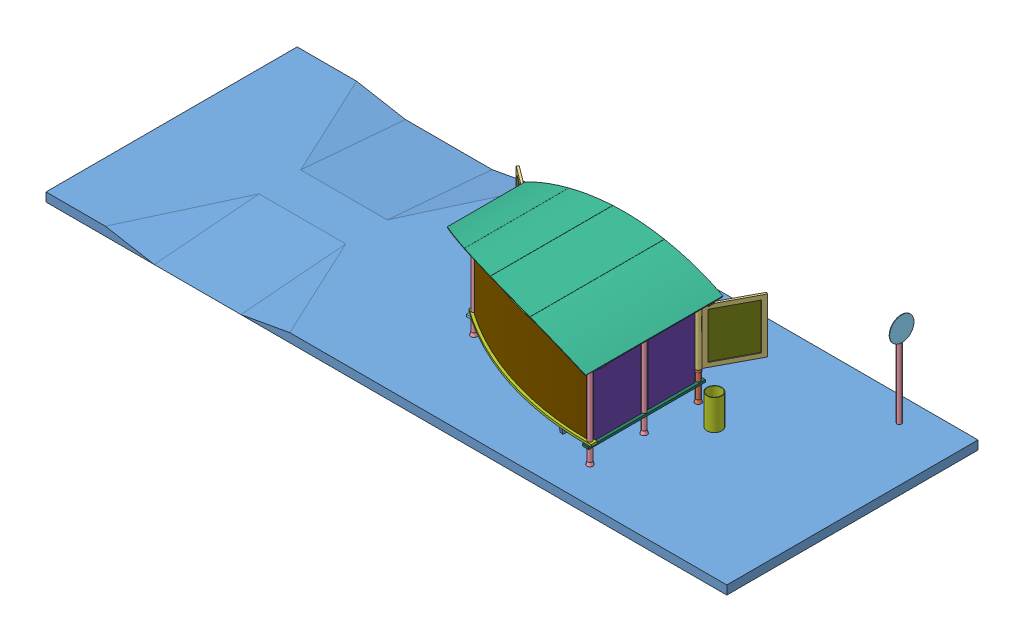
SolidWorks assembly Assem1, configuration Default. Lengths in mm.
Overall size (15720 3533.42 6503.13).
36 component instances, 25 part files, 159 mates.
Components (placement in the parent):
- Footh path-1: Footh path [Default] at (-2438.0582 7057.9484 15911.0305) size (15720 203.2 5800)
- Pole ring-1: Pole ring [Default] at (9292.5752 7335.7894 12581.0305) x (0.589726 0 -0.807604) z (0.807604 0 0.589726) size (140 2610 140)
- Frame-1: Frame [Default] at (9292.5752 7935.7894 12581.0305) x (0.469771 0 -0.882788) z (0.882788 0 0.469771) size (1235 1260 120)
- Pole-1: Pole [Default] at (9292.5752 7335.7894 13831.0305) x (0.069231 0 -0.997601) z (0.997601 0 0.069231) size (140 2610 140)
- Pole-2: Pole [Default] at (9292.5752 7335.7894 15081.0305) x (0.865127 0 -0.501553) z (0.501553 0 0.865127) size (140 2610 140)
- Pole ring-2: Pole ring [Default] at (5362.5752 7335.7894 12581.0305) x (0.936618 0 -0.350353) z (0.350353 0 0.936618) size (140 2610 140)
- Frame-2: Frame [Default] at (5362.5752 7935.7894 12581.0305) x (-0.801865 0 -0.597505) z (0.597505 0 -0.801865) size (1235 1260 120)
- Support small-3: Support small [Default] at (5292.5752 9335.7894 16511.0305) x (0 0 -1) z (0 -1 0) size (1450 140 50)
- Pole-3: Pole [Default] at (5362.5752 7335.7894 13831.0305) x (-0.993477 0 0.114032) z (-0.114032 0 -0.993477) size (140 2610 140)
- Support-1: Support [Default] at (5362.5752 9395.7894 12651.0305) x (1 0 0) z (0 1 0) size (4130 140 50)
- Curved long Support-1: Curved long Support [Default] at (9292.5752 9395.7894 15081.0305) x (0.865101 0 -0.501598) z (0 1 0) size (2988.63 3350.69 50)
- Curved long Support-2: Curved long Support [Default] at (9292.5752 7692.0618 15081.0305) x (0.865101 0 -0.501598) z (0 1 0) size (2988.63 3350.69 50)
- Curved long Shed 2-1: Curved long Shed 2 [Default] at (5878.003 7237.9254 16191.0495) x (1 0 0) z (0 1 0) size (4530 1976.71 909.5)
- Shed-1: Shed [Default] at (5362.5752 9395.7894 12651.0305) x (1 0 0) z (0 1 0) size (4530 140 567.45)
- Strips 1-1: Strips 1 [Default] at (-11146.362 19849.8743 2384.7532) x (0.892652 -0.450746 0) z (0 0 1) size (200 25 2933.57)
- Strips 2-3: Strips 2 [Default] at (-13429.2364 13763.5915 2384.7532) x (0.983949 -0.17845 0) z (0 0 1) size (200 25 2891)
- Strips 3-1: Strips 3 [Default] at (-13731.0289 8733.7477 2384.7532) x (0.998403 0.056486 0) z (0 0 1) size (200 25 2656.85)
- Strips 4-1: Strips 4 [Default] at (-12840.3126 4462.485 2384.7532) x (0.962952 0.269673 0) z (0 0 1) size (200 25 2167.26)
- Strips 5-1: Strips 5 [Default] at (-11819.7292 1327.6603 2384.7532) x (0.902606 0.430469 0) z (0 0 1) size (200 25 1693.64)
- Support Double-2: Support Double [Default] at (32225.5198 7642.0618 25262.0609) x (0 0 1) z (-1 0 0) size (2700 50 140)
- Support small-4: Support small [Default] at (5292.5752 7702.0618 9901.0305) x (0 0 1) z (0 1 0) size (1450 140 50)
- Support Double-3: Support Double [Default] at (32225.5198 9345.7894 25262.0609) x (0 0 1) z (-1 0 0) size (2700 50 140)
- Glass frame-2: Glass frame [Default] at (14070.0925 -425.359 3592.5383) x (0.469771 0 -0.882788) z (0.882788 0 0.469771) size (909.76 1060 10)
- Glass frame-3: Glass frame [Default] at (-2802.8168 -425.359 6502.8697) x (-0.801865 0 -0.597505) z (0.597505 0 -0.801865) size (909.76 1060 10)
- Glass-3: Glass [Default] at (5367.5752 -370.078 25234.791) x (0 0 1) z (-1 0 0) size (1092.11 1709.01 10)
- Glass-4: Glass [Default] at (9287.5752 -370.078 2415.1587) x (0 0 -1) z (1 0 0) size (1092.11 1709.01 10)
- Glass-5: Glass [Default] at (9287.5752 -370.078 1165.1587) x (0 0 -1) z (1 0 0) size (1092.11 1709.01 10)
- Glass back-1: Glass back [Default] at (9292.5752 9395.7894 15081.0305) x (-0.865101 0 0.501598) z (0 -1 0) size (2682.66 2948.43 1653.73)
- bench-3: bench [Default] at (9292.5752 7261.1484 8278.0705) x (0.573924 0 -0.818909) z (0.818909 0 0.573924) size (1386.88 534.65 3037.44)
- Ad-1: Ad [Default] at (5367.5752 -370.078 25234.791) x (0 0 -1) z (1 0 0) size (967.13 1402.54 20)
- Map-2: Map [Default] at (461.3046 8443.7494 -490.4565) x (0.998536 0 0.054083) z (0 1 0) size (746.38 115.58 600)
- RTPI-2: RTPI [Default] at (-2205.7822 9395.7894 9253.0974) x (1 0 0) z (0 -1 0) size (2045.3 249.56 600)
- Pole-4: Pole [Default] at (12031.85 7058.8113 10678.6301) size (140 2610 140)
- Sign board-2: Sign board [Default] at (11984.6264 -4.3155 21348.2902) x (-0.009112 0 0.999958) z (-0.999958 0 -0.009112) size (557.79 557.79 10)
- Part1-1: Part1 [Default] at (-13731.0289 8733.7477 12327.336) x (-0.998403 -0.056486 0) z (0 0 -1) size (4558.63 692.88 3411.91)
- Bin-1: Bin [Default] at (-2438.0582 7261.1484 15911.0305) x (1 0 0) z (0 1 0) size (342.37 342.37 700)
Mates (geometry in assembly coordinates):
- Coincident1: coincident: plane of Pole ring-1 through (9292.5752 9195.7894 12581.0305) normal (0 -1 0); plane of Frame-1 through (9269.0866 9195.7894 12625.1699) normal (0 1 0)
- Concentric2: concentric: cylinder of Pole ring-1 through (22932.9446 7761.1484 10181.0305) axis (0 -1 0) radius 50; cylinder of ? through (22932.9446 9671.1484 10181.0305) axis (0 1 0) radius 50
- Coincident3: coincident: plane of Pole ring-1 through (22932.9446 9671.1484 10181.0305) normal (0 1 0); plane of ? through (22862.9446 9671.1484 7501.0305) normal (0 -1 0)
- Concentric3: concentric: cylinder of Pole-1 through (22932.9446 7761.1484 11431.0305) axis (0 -1 0) radius 50; cylinder of ? through (22932.9446 9671.1484 11431.0305) axis (0 1 0) radius 50
- Concentric4: concentric: cylinder of Pole-2 through (22932.9446 7761.1484 12681.0305) axis (0 -1 0) radius 50; cylinder of ? through (22932.9446 9721.1484 12681.0305) axis (0 1 0) radius 50
- Concentric5: concentric: cylinder of Pole-1 through (22932.9446 7761.1484 11431.0305) axis (0 -1 0) radius 50; cylinder of ? through (22932.9446 9721.1484 11431.0305) axis (0 1 0) radius 50
- Coincident5: coincident: plane of ? through (22862.9446 9721.1484 7501.0305) normal (0 1 0); plane of ? through (23002.9446 9721.1484 15361.0305) normal (0 -1 0)
- Concentric6: concentric: cylinder of Pole ring-2 through (5362.5752 7335.7894 12581.0305) axis (0 -1 0) radius 50; cylinder of Frame-2 through (5362.5752 7935.7894 12581.0305) axis (0 -1 0) radius 50
- Coincident9: coincident: plane of Pole ring-2 through (5362.5752 7935.7894 12581.0305) normal (0 1 0); plane of Frame-2 through (5410.6871 7935.7894 12616.8808) normal (0 -1 0)
- Coincident12: coincident: circle of Support small-3; cylinder of Pole-3 through (5362.5752 7335.7894 13831.0305) axis (0 -1 0) radius 50
- Concentric7: concentric: cylinder of Pole ring-2 through (5362.5752 7335.7894 12581.0305) axis (0 -1 0) radius 50; cylinder of Support small-3 through (5362.5752 9395.7894 12581.0305) axis (0 -1 0) radius 50
- Concentric12: concentric: cylinder of Pole ring-1 through (9265.3997 7761.1484 10181.0305) axis (0 -1 0) radius 50; cylinder of ? through (9265.3997 7307.2509 10181.0305) axis (0 1 0) radius 50
- Concentric13: concentric: cylinder of Pole ring-2 through (5335.3997 7761.1484 10181.0305) axis (0 -1 0) radius 50; cylinder of ? through (5335.3997 7307.2509 10181.0305) axis (0 1 0) radius 50
- Perpendicular5: perpendicular: plane of Support small-3 through (5405.3997 9721.1484 11531.0305) normal (1 0 0); plane of ? through (9265.3997 7357.2509 10251.0305) normal (0 0 1)
- Parallel3: parallel: plane of ? through (22862.9446 9671.1484 11531.0305) normal (-1 0 0); plane of ? through (22862.9446 9721.1484 12781.0305) normal (-1 0 0)
- InPlace2: in place: plane of ? through (9215.5775 9871.1484 12676.8176) normal (0 1 0); plane of ? through (0 9871.1484 0) normal (0 1 0); moOrthogonalPlaneRef_w of ? through (9215.5775 9871.1484 12676.8176) normal (0 1 0); plane of ? through (0 9871.1484 0) normal (0 0 -1); plane of ? through (9215.5775 9871.1484 12676.8176) normal (0 1 0); plane of ? through (0 9871.1484 0) normal (1 0 0); plane of ? through (11383.7389 9871.1484 12693.4409) normal (0 1 0); unknown of ?
- Coincident31: coincident: plane of Pole-2; plane of ?
- Coincident32: coincident: moOrthogonalPlaneRef_w of Pole-2; plane of ? through (11432.1742 9871.1484 12681.0305) normal (-0.248209 0 -0.968706)
- Coincident33: coincident: moOrthogonalPlaneRef_w of Pole-2; plane of ? through (11432.1742 9871.1484 12681.0305) normal (0.968706 0 -0.248209)
- Concentric14: concentric: cylinder of Pole ring-1 through (9292.5752 7335.7894 12581.0305) axis (0 -1 0) radius 50; cylinder of Support-1 through (9292.5752 9395.7894 12581.0305) axis (0 1 0) radius 50
- Concentric15: concentric: cylinder of Pole ring-2 through (5362.5752 7335.7894 12581.0305) axis (0 -1 0) radius 50; cylinder of Support-1 through (5362.5752 9395.7894 12581.0305) axis (0 1 0) radius 50
- Perpendicular6: perpendicular: plane of Support small-3 through (5432.5752 9395.7894 13931.0305) normal (1 0 0); plane of Support-1 through (9292.5752 9445.7894 12651.0305) normal (0 0 1)
- Concentric16: concentric: cylinder of Pole-2 through (9292.5752 7335.7894 15081.0305) axis (0 -1 0) radius 50; cylinder of Curved long Support-1 through (9292.5752 9445.7894 15081.0305) axis (0 -1 0) radius 50
- Concentric17: concentric: cylinder of Pole-3 through (5362.5752 7335.7894 13831.0305) axis (0 -1 0) radius 50; cylinder of Curved long Support-1 through (5362.5752 9445.7894 13831.0305) axis (0 -1 0) radius 50
- Concentric38: concentric: cylinder of Support Double-3 through (9292.5752 9395.7894 15081.0305) axis (0 -1 0) radius 50; cylinder of Pole-2 through (9292.5752 7335.7894 15081.0305) axis (0 -1 0) radius 50
- Concentric19: concentric: cylinder of Pole-3 through (5362.5752 7335.7894 13831.0305) axis (0 -1 0) radius 50; cylinder of Curved long Support-2 through (5362.5752 7742.0618 13831.0305) axis (0 -1 0) radius 50
- Concentric21: concentric: cylinder of Pole-3 through (5362.5752 7335.7894 13831.0305) axis (0 -1 0) radius 50; cylinder of Curved long Shed 2-1 through (5362.5752 10237.9254 13831.0305) axis (0 -1 0) radius 50
- Tangent1: tangent: cylinder of Shed-1 through (9292.5752 9917.1343 12581.0305) axis (0 -1 0) radius 50; cylinder of Pole ring-1 through (9292.5752 7335.7894 12581.0305) axis (0 -1 0) radius 50
- Concentric22: concentric: cylinder of Pole ring-2 through (5362.5752 7335.7894 12581.0305) axis (0 -1 0) radius 50; cylinder of Shed-1 through (5362.5752 9917.1343 12581.0305) axis (0 -1 0) radius 50
- Concentric23: concentric: cylinder of Curved long Shed 2-1 through (7327.5752 4892.1343 13191.0495) axis (0 0 1) radius 5025; cylinder of Shed-1 through (7327.5752 4892.1343 12511.0305) axis (0 0 1) radius 5025
- Coincident45: coincident: line of Curved long Support-1 through (9392.5752 9445.7894 15150.3029) axis (0 0 -1); cylinder of Curved long Shed 2-1 through (7327.5752 4892.1343 13191.0495) axis (0 0 1) radius 5000
- Lock1: lock: unknown of Pole-2; unknown of Curved long Support-2
- InPlace3: in place: plane of assembly through (0 0 0) normal (0 0 1); plane of assembly through (0 0 0) normal (0 1 0); plane of assembly through (0 0 0) normal (1 0 0); unknown of assembly
- Coincident47: coincident: plane of ?; plane of assembly
- Coincident48: coincident: plane of ?; moOrthogonalPlaneRef_w of assembly through (0 0 0) normal (0 1 0)
- Coincident49: coincident: plane of ?; moOrthogonalPlaneRef_w of assembly through (0 0 0) normal (1 0 0)
- Tangent2: tangent: cylinder of Shed-1 through (7327.5752 4892.1343 12511.0305) axis (0 0 1) radius 5025; plane of Strips 1-1 through (-11146.362 19849.8743 2384.7532) normal (-0.450746 -0.892652 0)
- Tangent3: tangent: cylinder of Curved long Shed 2-1 through (7327.5752 4892.1343 13191.0495) axis (0 0 1) radius 5025; plane of Strips 1-1 through (-11146.362 19849.8743 2384.7532) normal (-0.450746 -0.892652 0)
- Coincident46: coincident: line of Shed-1 through (9592.5752 9377.7111 12511.0305) axis (0 0 1); line of Strips 1-1 through (9592.5752 9377.7111 15260.9099) axis (0 0 -1)
- Tangent4: tangent: cylinder of Shed-1 through (7327.5752 4892.1343 12511.0305) axis (0 0 1) radius 5025; plane of Strips 2-3 through (-13429.2364 13763.5915 2384.7532) normal (-0.17845 -0.983949 0)
- Parallel7: parallel: plane of Strips 1-1 through (9603.8438 9400.0275 12327.336) normal (0 0 -1); plane of Strips 2-3 through (8352.9117 9838.5581 12327.336) normal (0 0 -1)
- Tangent5: tangent: cylinder of Shed-1 through (7327.5752 4892.1343 12511.0305) axis (0 0 1) radius 5025; plane of Strips 3-1 through (-13731.0289 8733.7477 2384.7532) normal (0.056486 -0.998403 0)
- Tangent6: tangent: cylinder of Shed-1 through (7327.5752 4892.1343 12511.0305) axis (0 0 1) radius 5025; plane of Strips 4-1 through (-12840.3126 4462.485 2384.7532) normal (0.269673 -0.962952 0)
- Tangent7: tangent: cylinder of Shed-1 through (7327.5752 4892.1343 12511.0305) axis (0 0 1) radius 5025; plane of Strips 5-1 through (-11819.7292 1327.6603 2384.7532) normal (0.430469 -0.902606 0)
- InPlace4: in place: plane of ? through (0 0 0) normal (1 0 0); plane of ? through (0 0 0) normal (0 1 0); plane of ? through (0 0 0) normal (0 0 -1); unknown of ?
- Coincident49: coincident: plane of ?; plane of assembly
- Coincident50: coincident: plane of ? through (0 0 0) normal (0 1 0)
- Coincident51: coincident: plane of ? through (0 0 0) normal (0 0 -1)
- Concentric24: concentric: cylinder of Pole ring-1 through (9292.5752 7335.7894 12581.0305) axis (0 -1 0) radius 50; cylinder of Support Double-2 through (9292.5752 7692.0618 12581.0305) axis (0 -1 0) radius 50
- Concentric25: concentric: cylinder of Pole-2 through (9292.5752 7335.7894 15081.0305) axis (0 -1 0) radius 50; cylinder of Support Double-2 through (9292.5752 7692.0618 15081.0305) axis (0 -1 0) radius 50
- Coincident52: coincident: plane of Curved long Support-2 through (9292.5752 7692.0618 8278.0705) normal (0 -1 0); plane of Support Double-2 through (32225.5198 7692.0618 25262.0609) normal (0 1 0)
- Concentric26: concentric: cylinder of Pole-3 through (5362.5752 7335.7894 13831.0305) axis (0 -1 0) radius 50; cylinder of Support small-4 through (5362.5752 7642.0618 13831.0305) axis (0 1 0) radius 50
- Concentric27: concentric: cylinder of Pole ring-2 through (5362.5752 7335.7894 12581.0305) axis (0 -1 0) radius 50; cylinder of Support small-4 through (5362.5752 7642.0618 12581.0305) axis (0 1 0) radius 50
- Coincident53: coincident: plane of Support Double-2 through (32225.5198 7692.0618 25262.0609) normal (0 1 0); plane of Support small-4 through (5292.5752 7692.0618 9901.0305) normal (0 1 0)
- Concentric29: concentric: cylinder of Pole ring-1 through (9292.5752 7335.7894 12581.0305) axis (0 -1 0) radius 50; cylinder of Support Double-3 through (9292.5752 9395.7894 12581.0305) axis (0 -1 0) radius 50
- Coincident54: coincident: plane of Curved long Support-1 through (9292.5752 9395.7894 8278.0705) normal (0 -1 0); plane of Support Double-3 through (32225.5198 9395.7894 25262.0609) normal (0 1 0)
- InPlace5: in place: plane of ? through (0 0 0) normal (1 0 0); plane of ? through (0 0 0) normal (0 1 0); plane of ? through (0 0 0) normal (0 0 -1); unknown of ?
- Coincident57: coincident: plane of ?; plane of assembly
- Coincident58: coincident: plane of ? through (0 0 0) normal (0 1 0)
- Coincident59: coincident: plane of ? through (0 0 0) normal (0 0 -1)
- Coincident55: coincident: plane of Support small-3 through (5292.5752 9395.7894 16511.0305) normal (0 1 0); plane of Curved long Support-1 through (9292.5752 9395.7894 8278.0705) normal (0 -1 0)
- Coincident56: coincident: plane of Support-1 through (5362.5752 9395.7894 12651.0305) normal (0 -1 0); plane of Support Double-3 through (32225.5198 9395.7894 25262.0609) normal (0 1 0)
- Coincident57: coincident: plane of Pole-2 through (9249.3188 9445.7894 15106.1081) normal (0 1 0); plane of Curved long Support-1 through (9292.5752 9445.7894 8278.0705) normal (0 1 0)
- Coincident62: coincident: plane of Frame-1 through (9389.8083 8035.7894 12451.5286) normal (0.469771 0 -0.882788); plane of Glass frame-2 through (9372.1525 9095.7894 12442.1332) normal (-0.469771 0 0.882788)
- Distance1: distance = 20 mm: plane of Glass frame-2 through (14070.0925 -425.359 3592.5383) normal (-0.882788 0 -0.469771); plane of Frame-1 through (9242.3183 9195.7894 12622.2552) normal (-0.882788 0 -0.469771)
- Coincident64: coincident: plane of Frame-1 through (9819.649 8035.7894 11643.7775) normal (0 1 0); plane of Glass frame-2 through (9799.5313 8035.7894 11639.0086) normal (0 -1 0)
- Coincident65: coincident: plane of Frame-2 through (5249.2144 8035.7894 12465.383) normal (-0.801865 0 -0.597505); plane of Glass frame-3 through (5237.2643 9095.7894 12481.4203) normal (0.801865 0 0.597505)
- Distance2: distance = 20 mm: plane of Glass frame-3 through (-2802.8168 -425.359 6502.8697) normal (-0.597505 0 0.801865); plane of Frame-2 through (5395.7511 9195.7894 12636.9286) normal (-0.597505 0 0.801865)
- Coincident67: coincident: plane of Frame-2 through (4515.5079 8035.7894 11918.6657) normal (0 1 0); plane of Glass frame-3 through (4507.7603 8035.7894 11937.8345) normal (0 -1 0)
- InPlace6: in place: plane of ? through (0 0 0) normal (1 0 0); plane of ? through (0 0 0) normal (0 1 0); plane of ? through (0 0 0) normal (0 0 -1); unknown of ?
- Coincident68: coincident: plane of ?; plane of assembly
- Coincident69: coincident: plane of ? through (0 0 0) normal (0 1 0)
- Coincident70: coincident: plane of ? through (0 0 0) normal (0 0 -1)
- Coincident71: coincident: plane of Support small-3 through (18932.9446 9771.1484 14111.0305) normal (0 -1 0); plane of ? through (-1933.1628 9771.1484 10344.9253) normal (0 1 0)
- Distance3: distance = 75 mm: plane of Glass-3 through (5367.5752 -370.078 25234.791) normal (1 0 0); plane of Support small-4 through (5292.5752 7642.0618 13931.0305) normal (-1 0 0)
- Distance4: distance = 40 mm: plane of Glass-3 through (5357.5752 7692.0618 13741.0305) normal (0 0 1); cylinder of Pole-3 through (5362.5752 7335.7894 13831.0305) axis (0 -1 0) radius 50
- Coincident73: coincident: plane of Support small-4 through (5292.5752 7692.0618 9901.0305) normal (0 1 0); plane of Glass-3 through (5357.5752 7692.0618 13741.0305) normal (0 -1 0)
- Distance5: distance = 75 mm: plane of Support Double-2 through (9362.5752 7692.0618 12481.0305) normal (1 0 0); plane of Glass-4 through (9287.5752 -370.078 2415.1587) normal (-1 0 0)
- Coincident75: coincident: plane of Support Double-2 through (32225.5198 7692.0618 25262.0609) normal (0 1 0); plane of Glass-4 through (9297.5752 7692.0618 13908.9193) normal (0 -1 0)
- Distance6: distance = 30 mm: plane of Glass-4 through (9297.5752 7692.0618 15001.0305) normal (0 0 1); cylinder of Pole-2 through (9292.5752 7335.7894 15081.0305) axis (0 -1 0) radius 50
- Distance7: distance = 75 mm: plane of Glass-5 through (9287.5752 -370.078 1165.1587) normal (-1 0 0); plane of Support Double-2 through (9362.5752 7692.0618 12481.0305) normal (1 0 0)
- Coincident77: coincident: plane of Support Double-2 through (32225.5198 7692.0618 25262.0609) normal (0 1 0); plane of Glass-5 through (9297.5752 7692.0618 12658.9193) normal (0 -1 0)
- Concentric31: concentric: cylinder of Pole-1 through (9292.5752 7335.7894 13831.0305) axis (0 -1 0) radius 50; cylinder of Support Double-3 through (9292.5752 9395.7894 13831.0305) axis (0 -1 0) radius 50
- Distance8: distance = 30 mm: plane of Glass-5 through (9297.5752 7692.0618 13751.0305) normal (0 0 1); cylinder of Pole-1 through (9292.5752 7335.7894 13831.0305) axis (0 -1 0) radius 50
- Coincident92: coincident: plane of Strips 2-3 through (8352.9117 9838.5581 12327.336) normal (0 0 -1); plane of Strips 3-1 through (7167.0817 9941.1299 12327.336) normal (0 0 -1)
- Coincident93: coincident: plane of Strips 2-3 through (8352.9117 9838.5581 12327.336) normal (0 0 -1); plane of Strips 1-1 through (9603.8438 9400.0275 12327.336) normal (0 0 -1)
- Coincident94: coincident: plane of Strips 2-3 through (8352.9117 9838.5581 12327.336) normal (0 0 -1); plane of Strips 4-1 through (6154.8241 9807.9981 12327.336) normal (0 0 -1)
- Coincident95: coincident: plane of Strips 2-3 through (8352.9117 9838.5581 12327.336) normal (0 0 -1); plane of Strips 5-1 through (5231.4116 9487.3502 12327.336) normal (0 0 -1)
- Lock3: lock: unknown of Shed-1; unknown of Strips 2-3
- Lock4: lock: unknown of Curved long Shed 2-1; unknown of Strips 3-1
- Lock5: lock: unknown of Curved long Shed 2-1; unknown of Strips 2-3
- Lock6: lock: unknown of Curved long Shed 2-1; unknown of Strips 1-1
- Lock7: lock: unknown of Curved long Shed 2-1; unknown of Strips 5-1
- Lock8: lock: unknown of Curved long Shed 2-1; unknown of Strips 4-1
- InPlace7: in place: plane of ? through (22932.9446 9821.1484 5878.0705) normal (0 -1 0); plane of ? through (0 9821.1484 0) normal (0 -1 0); plane of ? through (22932.9446 9821.1484 5878.0705) normal (0 -1 0); plane of ? through (0 9821.1484 0) normal (0 0 -1); plane of ? through (22932.9446 9821.1484 5878.0705) normal (0 -1 0); plane of ? through (0 9821.1484 0) normal (-1 0 0); plane of Curved long Support-1 through (9292.5752 9395.7894 8278.0705) normal (0 -1 0); unknown of Glass back-1
- Coincident97: coincident: plane of Curved long Support-1; plane of Glass back-1
- Coincident98: coincident: moOrthogonalPlaneRef_w of Curved long Support-1 through (9292.5752 9395.7894 15081.0305) normal (-0.501598 0 -0.865101); plane of Glass back-1 through (9292.5752 9395.7894 15081.0305) normal (-0.501598 0 -0.865101)
- Coincident99: coincident: moOrthogonalPlaneRef_w of Curved long Support-1 through (9292.5752 9395.7894 15081.0305) normal (0.865101 0 -0.501598); plane of Glass back-1 through (9292.5752 9395.7894 15081.0305) normal (-0.865101 0 0.501598)
- InPlace8: in place: plane of ? through (21993.2812 10263.917 9927.336) normal (0 0 -1); plane of ? through (0 0 9927.336) normal (0 0 -1); plane of ? through (21993.2812 10263.917 9927.336) normal (0 0 -1); plane of ? through (0 0 9927.336) normal (0 1 0); plane of ? through (21993.2812 10263.917 9927.336) normal (0 0 -1); plane of ? through (0 0 9927.336) normal (-1 0 0); plane of ? through (8352.9117 10263.917 12327.336) normal (0 0 -1); unknown of ?
- Coincident100: coincident: plane of Strips 2-3; plane of ?
- Coincident101: coincident: moOrthogonalPlaneRef_w of Strips 2-3 through (-13429.2364 14188.9505 12327.336) normal (0.17845 0.983949 0); plane of ? through (-13429.2364 14188.9505 12327.336) normal (0.17845 0.983949 0)
- Coincident102: coincident: moOrthogonalPlaneRef_w of Strips 2-3 through (-13429.2364 14188.9505 12327.336) normal (0.983949 -0.17845 0); plane of ? through (-13429.2364 14188.9505 12327.336) normal (-0.983949 0.17845 0)
- Distance9: distance = 2400 mm: plane of Footh path-1 through (-2438.0582 7057.9484 10111.0305) normal (0 0 -1); plane of Support-1 through (5362.5752 9445.7894 12511.0305) normal (0 0 -1)
- Distance11: distance = 3919.3666 mm: plane of Support Double-2 through (9362.5752 7692.0618 12481.0305) normal (1 0 0); plane of Footh path-1 through (13281.9418 7057.9484 10111.0305) normal (1 0 0)
- Tangent16: tangent: plane of Strips 2-3 through (-13424.7751 14213.5492 2384.7532) normal (0.17845 0.983949 0); cylinder of ? through (6327.2602 5498.8428 13516.5607) axis (0 0 1) radius 5050.0679
- InPlace9: in place: plane of Footh path-1 through (-2438.0582 7261.1484 10111.0305) normal (0 1 0); plane of ? through (0 7261.1484 0) normal (0 1 0); plane of Footh path-1 through (-2438.0582 7261.1484 10111.0305) normal (0 1 0); plane of ? through (0 7261.1484 0) normal (0 0 -1); plane of Footh path-1 through (-2438.0582 7261.1484 10111.0305) normal (0 1 0); plane of ? through (0 7261.1484 0) normal (1 0 0); plane of Footh path-1 through (-2438.0582 7261.1484 10111.0305) normal (0 1 0); unknown of ?
- Coincident96: coincident: plane of Footh path-1; plane of ?
- Coincident97: coincident: moOrthogonalPlaneRef_w of Footh path-1 through (-2438.0582 7261.1484 15911.0305) normal (0 0 -1); plane of ? through (0 0 0) normal (0 0 -1)
- Coincident98: coincident: moOrthogonalPlaneRef_w of Footh path-1 through (-2438.0582 7261.1484 15911.0305) normal (-1 0 0); plane of ? through (0 0 0) normal (1 0 0)
- Coincident99: coincident: plane of Footh path-1 through (-2438.0582 7261.1484 10111.0305) normal (0 1 0); plane of ? through (9292.5752 7261.1484 8278.0705) normal (0 -1 0)
- Concentric32: concentric: cylinder of Curved long Support-2 through (9292.5752 8112.1398 8278.0705) axis (0 -1 0) radius 6732.96; cone of ? through (9292.5752 7741.1484 8278.0705) axis (0 -1 0)
- InPlace10: in place: plane of Footh path-1 through (-2438.0582 7261.1484 10111.0305) normal (0 1 0); plane of ? through (0 7261.1484 0) normal (0 1 0); plane of Footh path-1 through (-2438.0582 7261.1484 10111.0305) normal (0 1 0); plane of ? through (0 7261.1484 0) normal (0 0 -1); plane of Footh path-1 through (-2438.0582 7261.1484 10111.0305) normal (0 1 0); plane of ? through (0 7261.1484 0) normal (1 0 0); plane of Footh path-1 through (-2438.0582 7261.1484 10111.0305) normal (0 1 0); unknown of Bin-1
- Coincident101: coincident: plane of Footh path-1; plane of ?
- Coincident102: coincident: moOrthogonalPlaneRef_w of Footh path-1 through (-2438.0582 7261.1484 15911.0305) normal (0 0 -1); plane of Bin-1 through (-2438.0582 7261.1484 15911.0305) normal (0 0 -1)
- Coincident103: coincident: moOrthogonalPlaneRef_w of Footh path-1 through (-2438.0582 7261.1484 15911.0305) normal (-1 0 0); plane of Bin-1 through (-2438.0582 7261.1484 15911.0305) normal (1 0 0)
- Concentric33: concentric: cylinder of Curved long Support-2 through (9292.5752 8112.1398 8278.0705) axis (0 -1 0) radius 6732.96; cone of ? through (9292.5752 8724.591 8278.0705) axis (0 -1 0)
- Coincident104: coincident: plane of Footh path-1 through (-2438.0582 7261.1484 10111.0305) normal (0 1 0); plane of bench-3 through (8445.0121 7261.1484 14290.304) normal (0 -1 0)
- Lock10: lock: unknown of Footh path-1; unknown of bench-3
- InPlace11: in place: plane of ? through (5367.5752 0 25234.791) normal (1 0 0); plane of ? through (5367.5752 0 0) normal (1 0 0); plane of ? through (5367.5752 0 25234.791) normal (1 0 0); plane of ? through (5367.5752 0 0) normal (0 1 0); plane of ? through (5367.5752 0 25234.791) normal (1 0 0); plane of ? through (5367.5752 0 0) normal (0 0 -1); plane of Glass-3 through (5367.5752 -370.078 25234.791) normal (1 0 0); unknown of Ad-1
- Coincident105: coincident: plane of Glass-3; plane of Ad-1
- Coincident106: coincident: moOrthogonalPlaneRef_w of Glass-3 through (5367.5752 -370.078 25234.791) normal (0 1 0); plane of Ad-1 through (5367.5752 -370.078 25234.791) normal (0 1 0)
- Coincident107: coincident: moOrthogonalPlaneRef_w of Glass-3 through (5367.5752 -370.078 25234.791) normal (0 0 1); plane of Ad-1 through (5367.5752 -370.078 25234.791) normal (0 0 -1)
- InPlace12: in place: plane of ? through (0 0 0) normal (0 1 0); plane of ? through (0 0 0) normal (0 0 -1); plane of ? through (0 0 0) normal (1 0 0); unknown of ?
- Coincident108: coincident: plane of ?; plane of assembly
- Coincident109: coincident: plane of ? through (0 0 0) normal (0 0 -1)
- Coincident110: coincident: plane of ? through (0 0 0) normal (1 0 0)
- Concentric34: concentric: cylinder of Glass back-1 through (9292.5752 4125.9286 8278.0705) axis (0 1 0) radius 6802.96; cylinder of ? through (9292.5752 600 8278.0705) axis (0 -1 0) radius 6802.96
- Tangent17: tangent: cylinder of Glass back-1 through (9292.5752 4125.9286 8278.0705) axis (0 1 0) radius 6802.96; cylinder of ? through (9292.5752 600 8278.0705) axis (0 -1 0) radius 6802.96
- Concentric36: concentric: cylinder of Glass back-1 through (9292.5752 3755.8506 8278.0705) axis (0 1 0) radius 6802.96; cylinder of Map-2 through (9292.5752 9043.7494 8278.0705) axis (0 -1 0) radius 6802.96
- Lock11: lock: unknown of Glass back-1; unknown of Map-2
- InPlace13: in place: plane of ? through (5362.5752 9821.1484 12651.0305) normal (0 -1 0); plane of ? through (0 9821.1484 0) normal (0 -1 0); plane of ? through (5362.5752 9821.1484 12651.0305) normal (0 -1 0); plane of ? through (0 9821.1484 0) normal (0 0 -1); plane of ? through (5362.5752 9821.1484 12651.0305) normal (0 -1 0); plane of ? through (0 9821.1484 0) normal (-1 0 0); plane of ? through (5362.5752 9821.1484 12651.0305) normal (0 -1 0); unknown of Bin-1
- Coincident111: coincident: plane of Support-1; plane of ?
- Coincident112: coincident: moOrthogonalPlaneRef_w of Support-1 through (5362.5752 9821.1484 12651.0305) normal (0 0 -1); plane of Bin-1 through (-2438.0582 7261.1484 15911.0305) normal (0 0 -1)
- Coincident113: coincident: moOrthogonalPlaneRef_w of Support-1 through (5362.5752 9821.1484 12651.0305) normal (1 0 0); plane of Bin-1 through (-2438.0582 7261.1484 15911.0305) normal (1 0 0)
- Coincident114: coincident: plane of Support-1 through (5362.5752 9395.7894 12651.0305) normal (0 -1 0); plane of RTPI-2 through (-2205.7822 9395.7894 9253.0974) normal (0 1 0)
- Distance12: distance = 50 mm: plane of Support-1 through (5362.5752 9445.7894 12511.0305) normal (0 0 -1); plane of RTPI-2 through (7766.0087 8795.7894 12461.0305) normal (0 0 -1)
- Distance13: distance = 1826.5664 mm: plane of RTPI-2 through (7766.0087 8795.7894 12710.5895) normal (1 0 0); plane of Shed-1 through (9592.5752 9349.6868 12511.0305) normal (1 0 0)
- Lock12: lock: unknown of Footh path-1; unknown of Pole-4
- InPlace14: in place: plane of ? through (0 0 0) normal (1 0 0); plane of ? through (0 0 0) normal (0 1 0); plane of ? through (0 0 0) normal (0 0 -1); unknown of ?
- Coincident117: coincident: plane of ?; plane of assembly
- Coincident118: coincident: plane of ? through (0 0 0) normal (0 1 0)
- Coincident119: coincident: plane of ? through (0 0 0) normal (0 0 -1)
- Tangent18: tangent: cylinder of Pole-4 through (12031.85 7058.8113 10678.6301) axis (0 -1 0) radius 50; plane of Sign board-2 through (12081.9298 9164.4958 10670.1034) normal (0.999958 0 0.009112)
- Lock13: lock: unknown of Pole-4; unknown of Sign board-2
- InPlace15: in place: plane of ? through (7167.0817 10366.4889 12327.336) normal (0 0 -1); plane of ? through (0 0 12327.336) normal (0 0 -1); plane of ? through (7167.0817 10366.4889 12327.336) normal (0 0 -1); plane of ? through (0 0 12327.336) normal (0 1 0); plane of ? through (7167.0817 10366.4889 12327.336) normal (0 0 -1); plane of ? through (0 0 12327.336) normal (-1 0 0); plane of Strips 3-1 through (7167.0817 9941.1299 12327.336) normal (0 0 -1); unknown of Part1-1
- Coincident115: coincident: plane of Strips 3-1; plane of Part1-1
- Coincident116: coincident: moOrthogonalPlaneRef_w of Strips 3-1 through (-13731.0289 8733.7477 12327.336) normal (-0.056486 0.998403 0); plane of Part1-1 through (-13731.0289 8733.7477 12327.336) normal (-0.056486 0.998403 0)
- Coincident117: coincident: moOrthogonalPlaneRef_w of Strips 3-1 through (-13731.0289 8733.7477 12327.336) normal (0.998403 0.056486 0); plane of Part1-1 through (-13731.0289 8733.7477 12327.336) normal (-0.998403 -0.056486 0)
- Coincident123: coincident: plane of Footh path-1 through (-2438.0582 7261.1484 10111.0305) normal (0 1 0); circle of Pole ring-2
- Coincident125: coincident: plane of Footh path-1 through (-2438.0582 7261.1484 10111.0305) normal (0 1 0); circle of Pole-2
- Concentric37: concentric: cylinder of Curved long Support-2 through (9292.5752 7742.0618 15081.0305) axis (0 -1 0) radius 50; cylinder of Support Double-2 through (9292.5752 7692.0618 15081.0305) axis (0 -1 0) radius 50
- Coincident126: coincident: plane of Footh path-1 through (-2438.0582 7261.1484 10111.0305) normal (0 1 0); circle of Pole-3
- Coincident128: coincident: plane of Footh path-1 through (-2438.0582 7261.1484 10111.0305) normal (0 1 0); circle of Pole-1
- Coincident129: coincident: plane of Footh path-1 through (-2438.0582 7261.1484 10111.0305) normal (0 1 0); circle of Pole ring-1
- Concentric39: concentric: cylinder of Pole ring-1 through (9292.5752 7335.7894 12581.0305) axis (0 -1 0) radius 50; cylinder of Frame-1 through (9292.5752 7935.7894 12581.0305) axis (0 -1 0) radius 50
- InPlace16: in place: plane of Footh path-1 through (-2438.0582 7261.1484 10111.0305) normal (0 1 0); plane of ? through (0 7261.1484 0) normal (0 1 0); plane of Footh path-1 through (-2438.0582 7261.1484 10111.0305) normal (0 1 0); plane of ? through (0 7261.1484 0) normal (0 0 -1); plane of Footh path-1 through (-2438.0582 7261.1484 10111.0305) normal (0 1 0); plane of ? through (0 7261.1484 0) normal (1 0 0); plane of Footh path-1 through (-2438.0582 7261.1484 10111.0305) normal (0 1 0); unknown of Bin-1
- Coincident130: coincident: plane of Footh path-1; plane of Bin-1
- Coincident131: coincident: moOrthogonalPlaneRef_w of Footh path-1 through (-2438.0582 7261.1484 15911.0305) normal (0 0 -1); plane of Bin-1 through (-2438.0582 7261.1484 15911.0305) normal (0 0 -1)
- Coincident132: coincident: moOrthogonalPlaneRef_w of Footh path-1 through (-2438.0582 7261.1484 15911.0305) normal (-1 0 0); plane of Bin-1 through (-2438.0582 7261.1484 15911.0305) normal (1 0 0)
